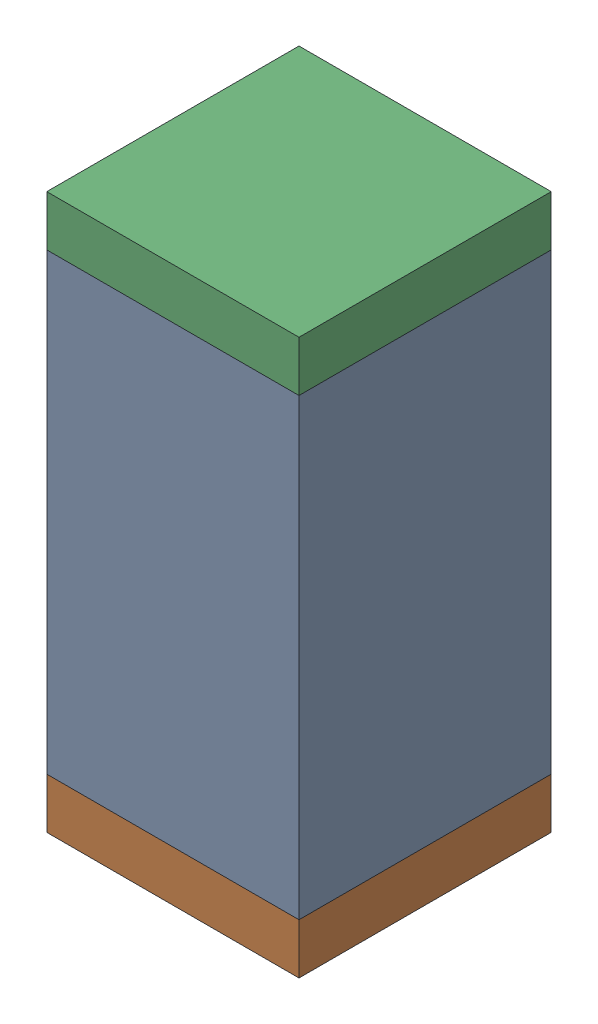
SolidWorks assembly C18, configuration Default. Lengths in mm.
Overall size (0.5 1.1 0.5).
6 component instances, 2 part files, 0 mates.
Components (placement in the parent):
- 791586336-1: 791586336 [Default] at (113.05 15.65 0) size (0.5 0.9 0.5)
  - Extruded_8-1: Extruded_8 [Default] at origin size (0.5 0.9 0.5)
- 810157360-1: 810157360 [Default] at (113.05 15.15 0) size (0.5 0.1 0.5)
  - Extruded_9-1: Extruded_9 [Default] at origin size (0.5 0.1 0.5)
- 810157360-2: 810157360 [Default] at (113.05 16.15 0) size (0.5 0.1 0.5)
  - Extruded_9-1: Extruded_9 [Default] at origin size (0.5 0.1 0.5)
